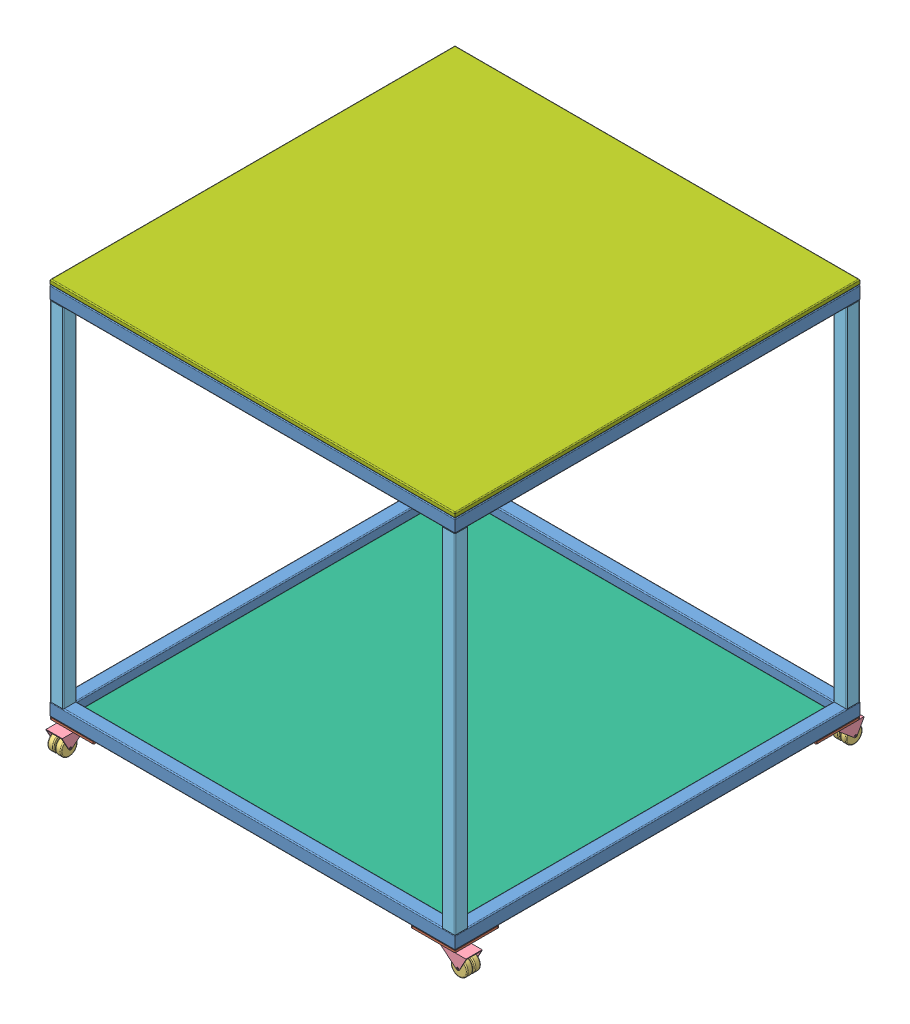
SolidWorks assembly PrepTable, configuration Default. Lengths in mm.
Overall size (1288.92 1233.97 1288.92).
32 component instances, 8 part files, 25 mates.
Components (placement in the parent):
- Frame-1: Frame [Default] at origin size (1220 40 1220)
- Wheel mount plate-5: Wheel mount plate [Default] at (-575 -6 -575) x (0 0 1) z (-1 0 0) size (132.22 6 132.22)
- Wheel mount plate-6: Wheel mount plate [Default] at (-575 -6 575) size (132.22 6 132.22)
- Wheel mount plate-7: Wheel mount plate [Default] at (575 -6 575) x (0 0 -1) z (1 0 0) size (132.22 6 132.22)
- Wheel mount plate-8: Wheel mount plate [Default] at (575 -6 -575) x (-1 0 0) z (0 0 -1) size (132.22 6 132.22)
- Caster wheel-3: Caster wheel [Default] at (-607.5 -53 -595.5) x (0.985694 -0.168545 0) z (0 0 1) size (95.01 85.72 60)
  - Wheel-1: Wheel [Default] at origin size (50 50 18)
  - Wheel-2: Wheel [Default] at (0 0 23) x (0.985694 0.168545 0) z (0 0 1) size (50 50 18)
  - Part7-1: Part7 [Default] at (0 0 41) x (0.985694 0.168545 0) z (0 0 1) size (87.5 52 60)
- Caster wheel-4: Caster wheel [Default] at (-595.5 -53 607.5) x (0 -0.168545 -0.985694) z (1 0 0) size (95.01 85.72 60)
  - Wheel-1: Wheel [Default] at origin size (50 50 18)
  - Wheel-2: Wheel [Default] at (0 0 23) x (0.985694 0.168545 0) z (0 0 1) size (50 50 18)
  - Part7-1: Part7 [Default] at (0 0 41) x (0.985694 0.168545 0) z (0 0 1) size (87.5 52 60)
- Caster wheel-5: Caster wheel [Default] at (607.5 -53 595.5) x (-0.985694 -0.168545 0) z (0 0 -1) size (95.01 85.72 60)
  - Wheel-1: Wheel [Default] at origin size (50 50 18)
  - Wheel-2: Wheel [Default] at (0 0 23) x (0.985694 0.168545 0) z (0 0 1) size (50 50 18)
  - Part7-1: Part7 [Default] at (0 0 41) x (0.985694 0.168545 0) z (0 0 1) size (87.5 52 60)
- Caster wheel-6: Caster wheel [Default] at (595.5 -53 -607.5) x (0 -0.168545 0.985694) z (-1 0 0) size (95.01 85.72 60)
  - Wheel-1: Wheel [Default] at origin size (50 50 18)
  - Wheel-2: Wheel [Default] at (0 0 23) x (0.985694 0.168545 0) z (0 0 1) size (50 50 18)
  - Part7-1: Part7 [Default] at (0 0 41) x (0.985694 0.168545 0) z (0 0 1) size (87.5 52 60)
- Frame-3: Frame [Default] at (0 1087 0) size (1220 40 1220)
- Part10-1: Part10 [Default] at (0 40 0) x (1 0 0) z (0 1 0) size (40 40 1047)
- Part10-2: Part10 [Default] at (0 40 0) x (0 0 -1) z (0 1 0) size (40 40 1047)
- Part10-3: Part10 [Default] at (0 40 0) x (-1 0 0) z (0 1 0) size (40 40 1047)
- Part10-4: Part10 [Default] at (0 40 0) x (0 0 1) z (0 1 0) size (40 40 1047)
- Part1-1: Part1 [Default] at (-575 0 575) x (1 0 0) z (0 1 0) size (1140 1140 15)
- Part2-1: Part2 [Default] at (0 1127 0) x (1 0 0) z (0 1 0) size (1220 1220 15)
- Part3-1: Part3 [Default] at (0 1127 0) x (-1 0 0) z (0 -1 0) size (70.71 70.71 6)
- Part3-5: Part3 [Default] at (0 1127 0) x (0 0 1) z (0 -1 0) size (70.71 70.71 6)
- Part3-6: Part3 [Default] at (0 1127 0) x (1 0 0) z (0 -1 0) size (70.71 70.71 6)
- Part3-7: Part3 [Default] at (0 1127 0) x (0 0 -1) z (0 -1 0) size (70.71 70.71 6)
Mates (geometry in assembly coordinates):
- Coincident7: coincident: plane of Wheel mount plate-5 through (-575 0 -575) normal (0 1 0); plane of Frame-1 through (0 0 0) normal (0 -1 0)
- Coincident8: coincident: plane of Frame-1 through (-610 40 -610) normal (-1 0 0); plane of Wheel mount plate-5 through (-610 0 -575) normal (-1 0 0)
- Coincident9: coincident: plane of Frame-1 through (-610 40 -610) normal (0 0 -1); plane of Wheel mount plate-5 through (-575 0 -610) normal (0 0 -1)
- Coincident10: coincident: plane of Wheel mount plate-5 through (-575 -6 -575) normal (0 -1 0); plane of Caster wheel-3/Part7-1 through (-607.5 -6 -554.5) normal (0 1 0)
- Distance2: distance = 5 mm: plane of Caster wheel-3/Part7-1 through (-605 -6 -605) normal (0 0 -1); plane of Wheel mount plate-5 through (-575 0 -610) normal (0 0 -1)
- Distance4: distance = 5 mm: plane of Wheel mount plate-5 through (-610 0 -575) normal (-1 0 0); plane of Caster wheel-3/Part7-1 through (-605 -6 -605) normal (-1 0 0)
- Distance5: distance = 15 mm: plane of Frame-3 through (0 1127 0) normal (0 1 0); plane of assembly through (595.5 1142 -607.5) normal (0 -1 0)
- Coincident12: coincident: line of Frame-1 through (-610 37 610) axis (0 -1 0); line of Frame-3 through (-610 1124 610) axis (0 -1 0)
- Coincident14: coincident: line of Frame-1 through (-610 37 -610) axis (0 -1 0); line of Frame-3 through (-610 1124 -610) axis (0 -1 0)
- InPlace1: in place: plane of Frame-1 through (0 40 0) normal (0 1 0); plane of Part10-1 through (0 40 0) normal (0 1 0); moOrthogonalPlaneRef_w of Frame-1 through (0 40 0) normal (0 1 0); plane of Part10-1 through (0 40 0) normal (0 0 -1); plane of Frame-1 through (0 40 0) normal (0 1 0); plane of Part10-1 through (0 40 0) normal (1 0 0); plane of Frame-1 through (0 40 0) normal (0 1 0); unknown of Part10-1
- Coincident15: coincident: plane of Frame-1; plane of Part10-1
- Coincident16: coincident: moOrthogonalPlaneRef_w of Frame-1 through (0 40 0) normal (0 0 -1); plane of Part10-1 through (0 40 0) normal (0 0 -1)
- Coincident17: coincident: moOrthogonalPlaneRef_w of Frame-1 through (0 40 0) normal (-1 0 0); plane of Part10-1 through (0 40 0) normal (1 0 0)
- InPlace2: in place: plane of Wheel mount plate-6 through (-575 0 575) normal (0 1 0); plane of ? through (0 0 0) normal (0 1 0); plane of Wheel mount plate-6 through (-575 0 575) normal (0 1 0); plane of ? through (0 0 0) normal (0 0 -1); plane of Wheel mount plate-6 through (-575 0 575) normal (0 1 0); plane of ? through (0 0 0) normal (1 0 0); plane of Wheel mount plate-6 through (-575 0 575) normal (0 1 0); unknown of Part1-1
- Coincident15: coincident: plane of Wheel mount plate-6; plane of Part1-1
- Coincident16: coincident: moOrthogonalPlaneRef_w of Wheel mount plate-6 through (-575 0 575) normal (0 0 -1); plane of Part1-1 through (-575 0 575) normal (0 0 -1)
- Coincident17: coincident: moOrthogonalPlaneRef_w of Wheel mount plate-6 through (-575 0 575) normal (-1 0 0); plane of Part1-1 through (-575 0 575) normal (1 0 0)
- InPlace3: in place: plane of Frame-3 through (0 1127 0) normal (0 1 0); plane of Part2-1 through (0 1127 0) normal (0 1 0); plane of Frame-3 through (0 1127 0) normal (0 1 0); plane of Part2-1 through (0 1127 0) normal (0 0 -1); plane of Frame-3 through (0 1127 0) normal (0 1 0); plane of Part2-1 through (0 1127 0) normal (1 0 0); plane of Frame-3 through (0 1127 0) normal (0 1 0); unknown of Part2-1
- Coincident18: coincident: plane of Frame-3; plane of Part2-1
- Coincident19: coincident: moOrthogonalPlaneRef_w of Frame-3 through (0 1127 0) normal (0 0 -1); plane of Part2-1 through (0 1127 0) normal (0 0 -1)
- Coincident20: coincident: moOrthogonalPlaneRef_w of Frame-3 through (0 1127 0) normal (-1 0 0); plane of Part2-1 through (0 1127 0) normal (1 0 0)
- InPlace4: in place: plane of Part2-1 through (0 1127 0) normal (0 -1 0); plane of Part3-1 through (0 1127 0) normal (0 -1 0); plane of Part2-1 through (0 1127 0) normal (0 -1 0); plane of Part3-1 through (0 1127 0) normal (0 0 -1); plane of Part2-1 through (0 1127 0) normal (0 -1 0); plane of Part3-1 through (0 1127 0) normal (-1 0 0); plane of Part2-1 through (0 1127 0) normal (0 -1 0); unknown of Part3-1
- Coincident21: coincident: plane of Part2-1; plane of Part3-1
- Coincident22: coincident: moOrthogonalPlaneRef_w of Part2-1 through (0 1127 0) normal (0 0 -1); plane of Part3-1 through (0 1127 0) normal (0 0 -1)
- Coincident23: coincident: moOrthogonalPlaneRef_w of Part2-1 through (0 1127 0) normal (1 0 0); plane of Part3-1 through (0 1127 0) normal (-1 0 0)
